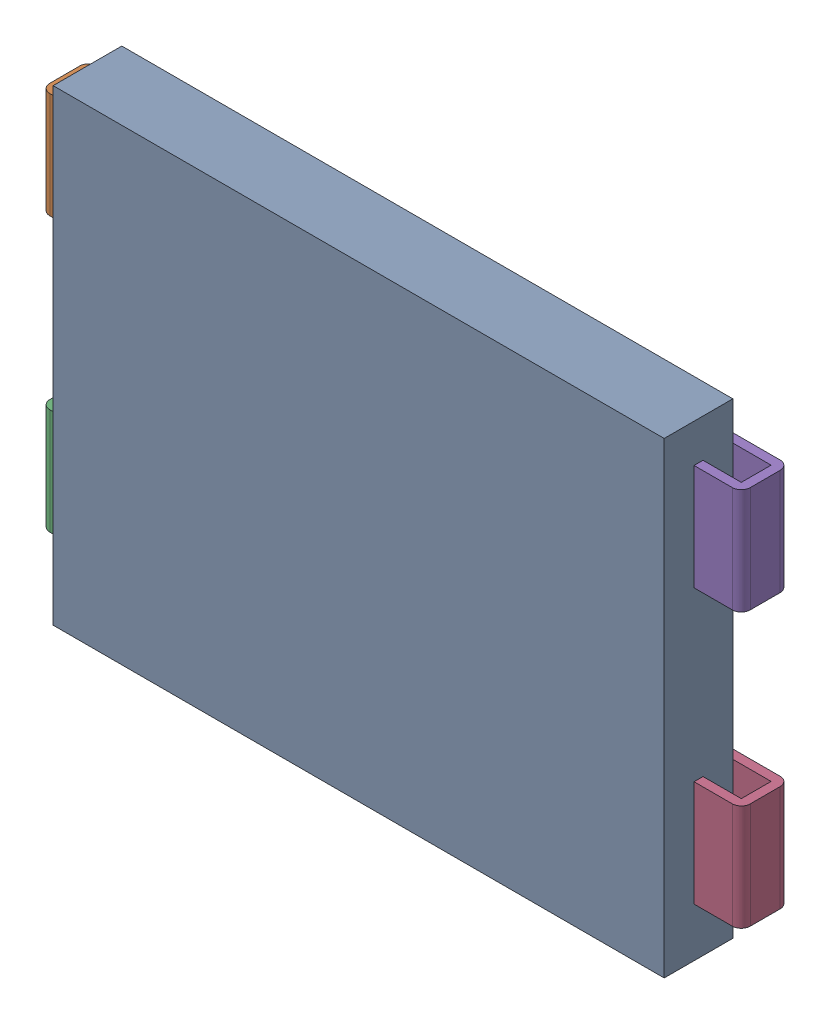
SolidWorks assembly M1, configuration Défaut. Lengths in mm.
Overall size (19.49 13 2.16).
6 component instances, 5 part files, 0 mates.
Components (placement in the parent):
- Open CASCADE STEP translator 6.8 1.27.1-1: Open CASCADE STEP translator 6.8 1.27.1 [Défaut] at origin size (19.49 13 2.16)
  - Body_1_13-1: Body_1_13 [Défaut] at origin size (17 13 1.91)
  - Pin_1_10-1: Pin_1_10 [Défaut] at (-31.75 0 0) x (-1 0 0) z (0 0 1) size (3.61 2.95 1.33)
  - Pin_2_10-1: Pin_2_10 [Défaut] at (-31.75 -15.24 0) x (-1 0 0) z (0 0 1) size (3.61 2.95 1.33)
  - Pin_3_6-1: Pin_3_6 [Défaut] at origin size (3.61 2.95 1.33)
  - Pin_4_4-1: Pin_4_4 [Défaut] at origin size (3.61 2.95 1.33)
